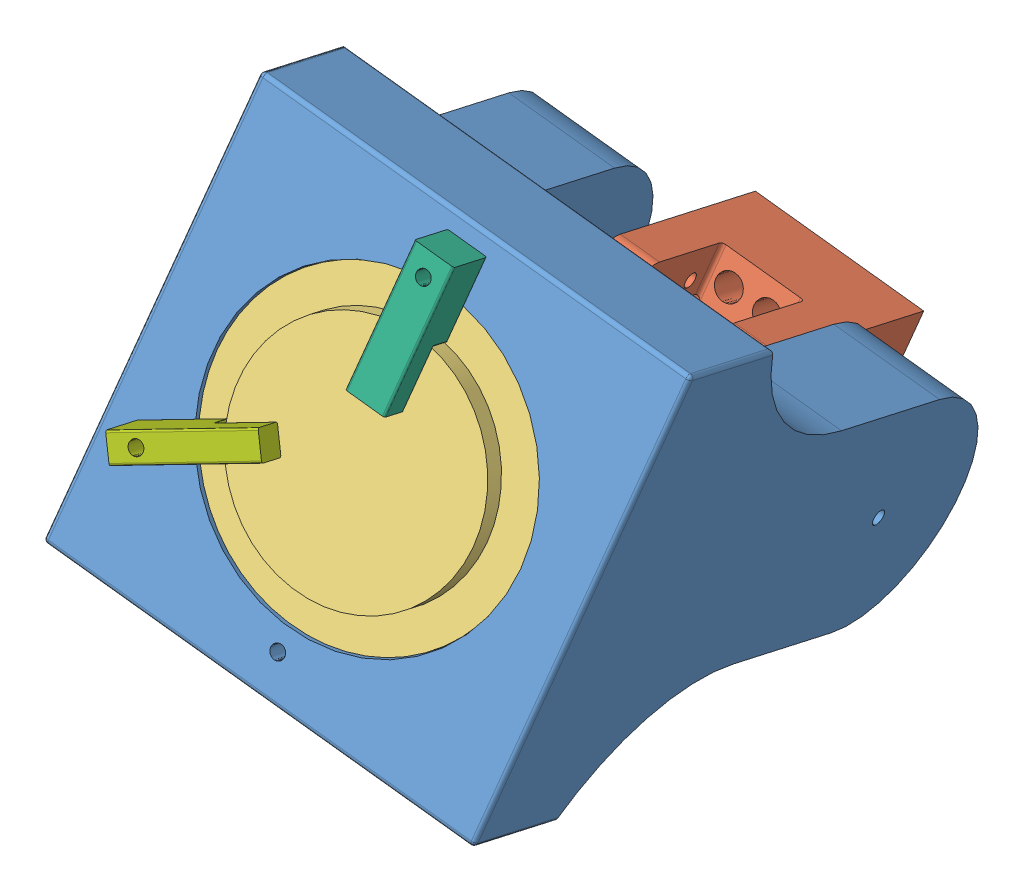
SolidWorks assembly Shadi Discussed Smaller Design - most recent assembly, configuration Default. Lengths in mm.
Overall size (149.34 171.79 178.29).
7 component instances, 7 part files, 20 mates.
Components (placement in the parent):
- Platform_Shaker_COPYNEW_ShadiApproved_Smaller-1: Platform_Shaker_COPYNEW_ShadiApproved_Smaller [Default] at (72.8667 52.3081 84.9518) x (0.96976 -0.223218 -0.098687) z (0.172494 0.340802 0.924175) size (110 110 137.25)
- Servo Mount-1: Servo Mount [Default] at (41.6512 32.9099 -22.8786) x (0.172659 0.913251 -0.368999) z (0.96976 -0.223218 -0.098687) size (65 55 43)
- Outline for Chamber-1: Outline for Chamber [Default] at (73.5567 53.6713 88.6485) x (0.981445 -0.139228 -0.13184) z (0.08374 0.929769 -0.358494) size (78 14 78)
- Servo Arm to Use-1: Servo Arm to Use [Default] at (26.9266 21.5459 -13.1781) x (0.172494 0.340802 0.924175) z (-0.172659 -0.913251 0.368999) size (34 7 15)
- Servomotor- Shadi Approved-2: Servomotor- Shadi Approved [Default] at (52.6315 17.2275 -5.563) x (0.172659 0.913251 -0.368999) z (-0.96976 0.223218 0.098687) size (54.5 20 47.4)
- Clamp_Shaker_v2-1: Clamp_Shaker_v2 [Default] at (79.427 84.1494 77.3957) x (-0.172659 -0.913251 0.368999) z (0.172494 0.340802 0.924175) size (35 10 12)
- Small_Clamp-4: Small_Clamp [Default] at (42.4003 49.8165 104.5416) x (-0.901611 -0.323204 0.287468) z (-0.172494 -0.340802 -0.924175) size (35 7 12)
Mates (geometry in assembly coordinates):
- Parallel3: parallel aligned: plane of Platform_Shaker_COPYNEW_ShadiApproved_Smaller-1 through (23.8514 104.5899 42.3594) normal (0.172659 0.913251 -0.368999); plane of Servo Mount-1 through (54.8518 41.0314 -12.8616) normal (0.172659 0.913251 -0.368999)
- Parallel4: parallel aligned: plane of Servo Mount-1 through (87.4813 34.9047 -12.7571) normal (0.172494 0.340802 0.924175); plane of Servomotor- Shadi Approved-2 through (52.6315 17.2275 -5.563) normal (0.172494 0.340802 0.924175)
- Concentric14: concentric aligned: circle of Servomotor- Shadi Approved-2; circle of Servo Mount-1
- Concentric15: concentric aligned: circle of Servo Mount-1; circle of Servomotor- Shadi Approved-2
- Coincident65: coincident anti-aligned: plane of Servo Mount-1 through (44.1183 37.7841 -9.6608) normal (-0.96976 0.223218 0.098687); plane of Servomotor- Shadi Approved-2 through (40.496 31.0566 -30.0385) normal (0.96976 -0.223218 -0.098687)
- ProfileCenter36: profile center aligned: circle of Small_Clamp-1; circle of Platform_Shaker_COPYNEW_ShadiApproved_Smaller-1
- ProfileCenter38: profile center anti-aligned: plane of Outline for Chamber-1 through (71.1418 48.9001 75.71) normal (-0.172494 -0.340802 -0.924175); plane of Platform_Shaker_COPYNEW_ShadiApproved_Smaller-1 through (71.1418 48.9001 75.71) normal (0.172494 0.340802 0.924175)
- ProfileCenter39: profile center aligned: circle of Clamp_Shaker_v2-1; circle of Platform_Shaker_COPYNEW_ShadiApproved_Smaller-1
- Parallel6: parallel aligned: plane of Platform_Shaker_COPYNEW_ShadiApproved_Smaller-1 through (23.8514 104.5899 42.3594) normal (0.172659 0.913251 -0.368999); plane of Clamp_Shaker_v2-1 through (78.8071 103.633 77.9009) normal (0.172659 0.913251 -0.368999)
- Parallel7: parallel: plane of Servo Mount-1 through (69.5938 -37.6241 -24.4795) normal (-0.172659 -0.913251 0.368999); plane of BA2s5 Cad to use-1 through (38.3799 40.8829 29.5759) normal (0 -1 0)
- Concentric23: concentric anti-aligned: circle of BA2s5 Cad to use-1; circle of Second Platform Thorr Labs-1
- Parallel8: parallel: plane of BA2s5 Cad to use-1 through (38.3799 40.8829 29.5759) normal (-1 0 0); plane of Second Platform Thorr Labs-1
- Concentric24: concentric aligned: circle of Platform_Shaker_COPYNEW_ShadiApproved_Smaller-1; circle of Small_Clamp-3
- ProfileCenter40: profile center aligned: circle of Small_Clamp-4; circle of Platform_Shaker_COPYNEW_ShadiApproved_Smaller-1
- Concentric26: concentric aligned: circle of Servo Arm to Use-1; circle of Servomotor- Shadi Approved-2
- Coincident76: coincident anti-aligned: plane of Servo Arm to Use-1 through (26.9266 21.5459 -13.1781) normal (0.96976 -0.223218 -0.098687); plane of Servomotor- Shadi Approved-2 through (20.0219 -9.2597 -11.3499) normal (-0.96976 0.223218 0.098687)
- Coincident78: coincident anti-aligned: plane of Platform_Shaker_COPYNEW_ShadiApproved_Smaller-1 through (24.226 31.2978 9.1578) normal (0.96976 -0.223218 -0.098687); plane of Servo Arm to Use-1 through (20.1383 23.1084 -12.4873) normal (-0.96976 0.223218 0.098687)
- Coincident79: coincident anti-aligned: plane of Platform_Shaker_COPYNEW_ShadiApproved_Smaller-1 through (21.8381 28.1604 -7.2112) normal (-0.172659 -0.913251 0.368999); plane of Servo Arm to Use-1 through (21.8381 28.1604 -7.2112) normal (0.172659 0.913251 -0.368999)
- Concentric28: concentric aligned: cylinder of Platform_Shaker_COPYNEW_ShadiApproved_Smaller-1 through (24.226 31.2978 9.1578) axis (0.96976 -0.223218 -0.098687) radius 3; cylinder of Servo Arm to Use-1 through (24.226 31.2978 9.1578) axis (0.96976 -0.223218 -0.098687) radius 3
- Parallel10: parallel aligned: plane of Platform_Shaker_COPYNEW_ShadiApproved_Smaller-1 through (4.8588 4.1322 82.9493) normal (-0.96976 0.223218 0.098687); plane of BA2s5 Cad to use-2 through (44.7332 40.8406 39.3192) normal (-1 0 0)
